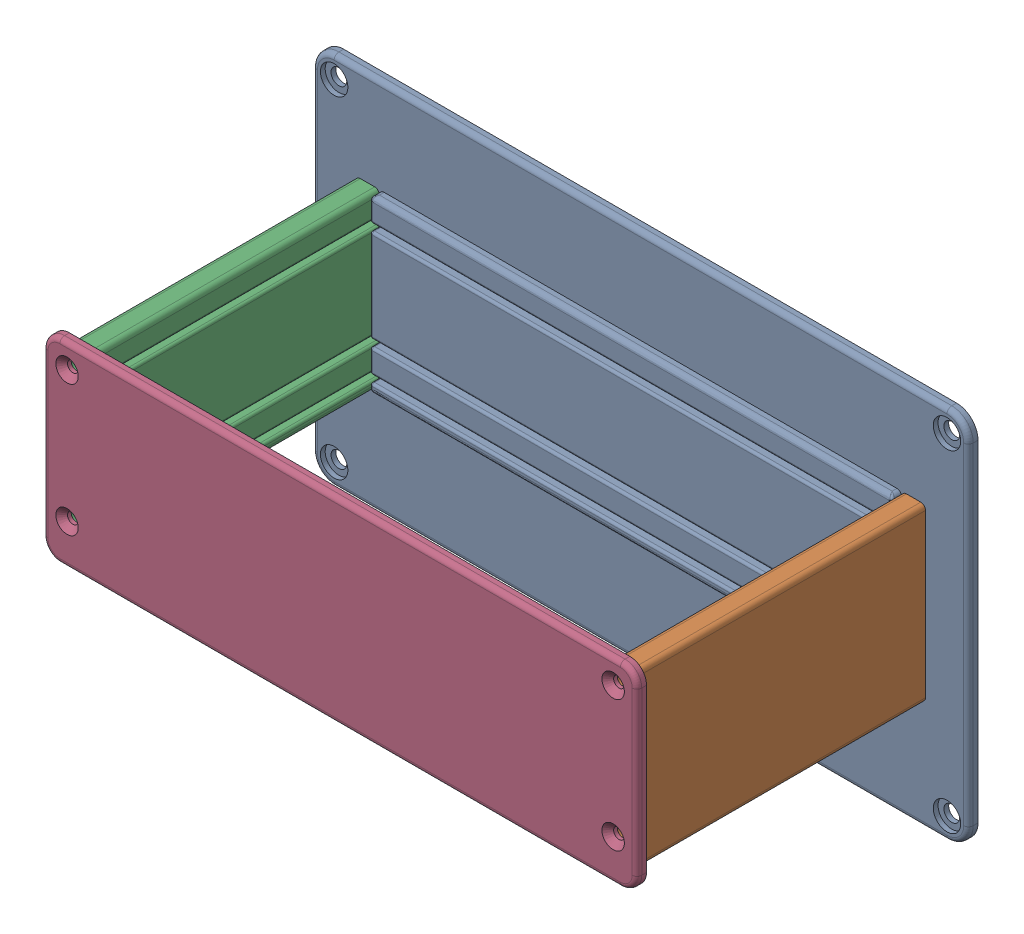
SolidWorks assembly Assemblage2, configuration Défaut. Lengths in mm.
Overall size (275 157 130).
4 component instances, 3 part files, 20 mates.
Components (placement in the parent):
- socle2-1: socle2 [Défaut] at (0.0461 -3.1056 995.9132) size (275 157 8.17)
- pilier-1: pilier [Défaut] at (116.4565 -0.2145 999.9132) x (0 1 0) z (0 0 1) size (72 10 122)
- pilier-2: pilier [Défaut] at (-116.3643 -0.2145 1121.9132) x (0 1 0) z (0 0 -1) size (72 10 122)
- couvercle-2: couvercle [Défaut] at (0.0461 -0.1056 1121.9132) size (249 82 4)
Mates (geometry in assembly coordinates):
- Coïncidente1: coincident anti-aligned: plane of socle2-1 through (0.0461 -3.1056 999.9132) normal (0 0 1); plane of pilier-1 through (116.4565 -0.2145 999.9132) normal (0 0 -1)
- Coaxiale1: concentric anti-aligned: circle of socle2-1; circle of pilier-1
- Coaxiale2: concentric anti-aligned: circle of socle2-1; circle of pilier-1
- Coïncidente2: coincident anti-aligned: plane of socle2-1 through (109.5461 -3.1056 1003.9132) normal (1 0 0); plane of pilier-1 through (109.5461 -36.1056 1121.9132) normal (-1 0 0)
- Coïncidente3: coincident anti-aligned: plane of socle2-1 through (109.5461 -3.1056 1003.9132) normal (1 0 0); plane of pilier-1 through (109.5461 -29.1056 1121.9132) normal (-1 0 0)
- Coïncidente4: coincident anti-aligned: plane of socle2-1 through (109.5461 -3.1056 1003.9132) normal (1 0 0); plane of pilier-1 through (109.5461 -16.1056 1121.9132) normal (-1 0 0)
- Coïncidente5: coincident anti-aligned: plane of socle2-1 through (109.5461 -3.1056 1003.9132) normal (1 0 0); plane of pilier-1 through (109.5461 25.8944 1121.9132) normal (-1 0 0)
- Coïncidente6: coincident anti-aligned: plane of socle2-1 through (0.0461 -3.1056 999.9132) normal (0 0 1); plane of pilier-2 through (-116.3643 -0.2145 999.9132) normal (0 0 -1)
- Coaxiale3: concentric aligned: circle of socle2-1; circle of pilier-2
- Coaxiale4: concentric aligned: circle of socle2-1; circle of pilier-2
- Coïncidente7: coincident anti-aligned: plane of socle2-1 through (-109.4539 -3.1056 1003.9132) normal (-1 0 0); plane of pilier-2 through (-109.4539 25.8944 999.9132) normal (1 0 0)
- Coïncidente8: coincident anti-aligned: plane of socle2-1 through (-109.4539 -3.1056 1003.9132) normal (-1 0 0); plane of pilier-2 through (-109.4539 -16.1056 999.9132) normal (1 0 0)
- Coïncidente9: coincident anti-aligned: plane of socle2-1 through (-109.4539 -3.1056 1003.9132) normal (-1 0 0); plane of pilier-2 through (-109.4539 -29.1056 999.9132) normal (1 0 0)
- Coïncidente10: coincident anti-aligned: plane of socle2-1 through (-109.4539 -3.1056 1003.9132) normal (-1 0 0); plane of pilier-2 through (-109.4539 -36.1056 999.9132) normal (1 0 0)
- Coïncidente12: coincident anti-aligned: plane of pilier-1 through (116.4565 -0.2145 1121.9132) normal (0 0 1); plane of couvercle-2 through (0.0461 -0.1056 1121.9132) normal (0 0 -1)
- Coïncidente13: coincident anti-aligned: plane of pilier-2 through (-116.3643 -0.2145 1121.9132) normal (0 0 1); plane of couvercle-2 through (0.0461 -0.1056 1121.9132) normal (0 0 -1)
- Coaxiale5: concentric anti-aligned: circle of pilier-2; circle of couvercle-2
- Coaxiale6: concentric anti-aligned: circle of pilier-2; circle of couvercle-2
- Coaxiale7: concentric aligned: circle of pilier-1; circle of couvercle-2
- Coaxiale8: concentric aligned: circle of pilier-1; circle of couvercle-2
